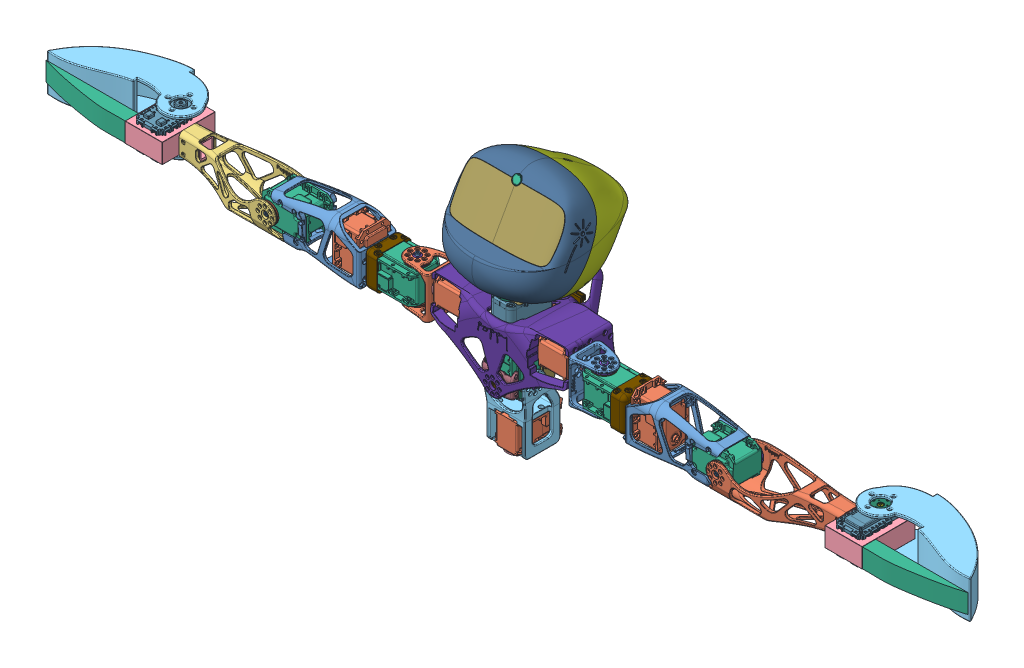
SolidWorks assembly Poppy_Humanoid_Torso_Modify, configuration Default. Lengths in mm.
Overall size (1063.03 305.58 172.17).
144 component instances, 42 part files, 6 mates.
Components (placement in the parent):
- spine-1: spine [Default] at (0 138.4875 17) size (49.29 92.85 54.86)
  - MX-28(T)-2-1: MX-28(T)-2 [Default] x (1 0 0) z (0 -1 0) size (35.6 54.13 45.1)
    - WB_M2.5x8-1: WB_M2.5x8 [Default] at (0 0 25.85) x (0 0 -1) z (-0.991137 0.132843 0) size (10.5 4.5 4.5)
    - dynamixel_x28series(Défaut)-1: dynamixel_x28series(Défaut) [Default] at origin size (35.6 50.71 41.85)
    - trust_washer(Défaut)-1: trust_washer(Défaut) [Default] at (0 0 18.6) x (-0.666375 -0.745617 0) z (0.745617 -0.666375 0) size (22 0.85 22)
    - HN07-N101(Défaut)-1: HN07-N101(Défaut) [Default] at (0 0 18.5) x (1 0 0) z (0 -1 0) size (22 5.85 22)
  - spine-1: spine [Default] at (0 15 0.8) x (-1 0 0) z (0 0 -1) size (49.29 83.95 45.1)
- double_rotation(full_MX28)-1: double_rotation(full_MX28) [Default] at (0 192.4875 19.8) size (48.5 54.13 85.1)
  - MX-28(U)-6-1: MX-28(U)-6 [Default] x (0 0 1) z (1 0 0) size (35.6 54.13 48.5)
    - dynamixel_x28series(U)-1: dynamixel_x28series(U) [Default] at origin size (35.6 50.71 41.85)
    - trust_washer(U)-1: trust_washer(U) [Default] at (0 0 18.6) x (-0.666375 -0.745617 0) z (0.745617 -0.666375 0) size (22 0.85 22)
    - HN07-N101(U)-1: HN07-N101(U) [Default] at (0 0 18.5) x (1 0 0) z (0 -1 0) size (22 5.85 22)
    - WB_M2.5x8-1: WB_M2.5x8 [Default] at (0 0 25.85) x (0 0 -1) z (-0.991137 0.132843 0) size (10.5 4.5 4.5)
    - WB_M2.5x8-2: WB_M2.5x8 [Default] at (0 0 -22.65) x (0 0 1) z (-0.936501 0.350665 0) size (10.5 4.5 4.5)
    - RX28-CAP-1: RX28-CAP [Default] at (0 0 -20.35) x (-0.995735 -0.092256 0) z (0 0 -1) size (7.2 7.2 1.8)
    - MF106ZZ-1: MF106ZZ [Default] at (0 0 -20.35) x (0.888333 -0.4592 0) z (-0.4592 -0.888333 0) size (11.2 3 11.2)
    - HN07-i101-1: HN07-i101 [Default] at (0 0 -20.5) x (1 0 0) z (0 1 0) size (22 3.05 22)
  - MX-28(T)-3-1: MX-28(T)-3 [Default] at (0 0 -37) x (1 0 0) z (0 0 -1) size (35.6 54.13 45.1)
    - WB_M2.5x8-1: WB_M2.5x8 [Default] at (0 0 25.85) x (0 0 -1) z (-0.991137 0.132843 0) size (10.5 4.5 4.5)
    - dynamixel_x28series(Défaut)-1: dynamixel_x28series(Défaut) [Default] at origin size (35.6 50.71 41.85)
    - trust_washer(Défaut)-1: trust_washer(Défaut) [Default] at (0 0 18.6) x (-0.666375 -0.745617 0) z (0.745617 -0.666375 0) size (22 0.85 22)
    - HN07-N101(Défaut)-1: HN07-N101(Défaut) [Default] at (0 0 18.5) x (1 0 0) z (0 -1 0) size (22 5.85 22)
  - i101_Set(FR07)-1: i101_Set(FR07) [Default] at (0 0 21.6) x (-0.798096 0.60253 0) z (0 0 1) size (22 22 3.8)
    - RX28-CAP-1: RX28-CAP [Default] at (0 0 -0.15) size (7.2 7.2 1.8)
    - MF106ZZ-1: MF106ZZ [Default] at (0 0 -0.15) x (-0.837169 0.546944 0) z (-0.546944 -0.837169 0) size (11.2 3 11.2)
    - HN07-i101-1: HN07-i101 [Default] x (1 0 0) z (0 -1 0) size (22 3.05 22)
  - double_rotation_link(double_MX28)-1: double_rotation_link(double_MX28) [Default] at (0 -0.5 0) size (7.4 26.51 14.1)
  - double_rotation_link(double_MX28)-2: double_rotation_link(double_MX28) [Default] at (0 8.5 0) x (-1 0 0) z (0 0 1) size (7.4 26.51 14.1)
  - i101-Set_to_MX_link(MX28_compatible)-1: i101-Set_to_MX_link(MX28_compatible) [Default] x (0 0 -1) z (1 0 0) size (8.29 28.53 35.81)
- chest-1: chest [Default] at (7.2825 216.5654 -159.6611) size (167.7 95.79 102.98)
  - AX-12_18A-1: AX-12_18A [Default] at (-7.2825 38.9221 184.4611) x (-1 0 0) z (0 1 0) size (32 50.04 40.32)
    - dynamixel_AXseries-1: dynamixel_AXseries [Default] at origin size (32 50.04 38.37)
    - AX12_horn-1: AX12_horn [Default] at (0 0 19.1) x (0 1 0) z (0 0 1) size (22 22 6.7)
    - BHS_M2_6X8-1: BHS_M2_6X8 [Default] at (0 0 19.55) x (0.628847 -0.777529 0) z (-0.777529 -0.628847 0) size (5.5 9.6 5.5)
  - MX-28(T)-4-1: MX-28(T)-4 [Default] at (-65.2825 25.9221 183.4611) x (0 -1 0) z (-1 0 0) size (35.6 54.13 45.1)
    - WB_M2.5x8-1: WB_M2.5x8 [Default] at (0 0 25.85) x (0 0 -1) z (-0.991137 0.132843 0) size (10.5 4.5 4.5)
    - dynamixel_x28series(Défaut)-1: dynamixel_x28series(Défaut) [Default] at origin size (35.6 50.71 41.85)
    - trust_washer(Défaut)-1: trust_washer(Défaut) [Default] at (0 0 18.6) x (-0.666375 -0.745617 0) z (0.745617 -0.666375 0) size (22 0.85 22)
    - HN07-N101(Défaut)-1: HN07-N101(Défaut) [Default] at (0 0 18.5) x (1 0 0) z (0 -1 0) size (22 5.85 22)
  - MX-28(T)-5-1: MX-28(T)-5 [Default] at (50.7175 25.9221 183.4611) x (0 1 0) z (1 0 0) size (35.6 54.13 45.1)
    - WB_M2.5x8-1: WB_M2.5x8 [Default] at (0 0 25.85) x (0 0 -1) z (-0.991137 0.132843 0) size (10.5 4.5 4.5)
    - dynamixel_x28series(Défaut)-1: dynamixel_x28series(Défaut) [Default] at origin size (35.6 50.71 41.85)
    - trust_washer(Défaut)-1: trust_washer(Défaut) [Default] at (0 0 18.6) x (-0.666375 -0.745617 0) z (0.745617 -0.666375 0) size (22 0.85 22)
    - HN07-N101(Défaut)-1: HN07-N101(Défaut) [Default] at (0 0 18.5) x (1 0 0) z (0 -1 0) size (22 5.85 22)
  - chest-1: chest [Default] at (-7.2825 -24.0779 121.9611) size (157.02 95.79 102.98)
- shoulder_x-1: shoulder_x [Default] at (119.9166 235.6125 35.5145) x (0 0 -1) z (0 1 0) size (38.6 59.63 48.85)
  - MX-28(U)-7-1: MX-28(U)-7 [Default] at (11.7145 14.4166 -1.625) size (35.6 54.13 48.5)
    - dynamixel_x28series(U)-1: dynamixel_x28series(U) [Default] at origin size (35.6 50.71 41.85)
    - trust_washer(U)-1: trust_washer(U) [Default] at (0 0 18.6) x (-0.666375 -0.745617 0) z (0.745617 -0.666375 0) size (22 0.85 22)
    - HN07-N101(U)-1: HN07-N101(U) [Default] at (0 0 18.5) x (1 0 0) z (0 -1 0) size (22 5.85 22)
    - WB_M2.5x8-1: WB_M2.5x8 [Default] at (0 0 25.85) x (0 0 -1) z (-0.991137 0.132843 0) size (10.5 4.5 4.5)
    - WB_M2.5x8-2: WB_M2.5x8 [Default] at (0 0 -22.65) x (0 0 1) z (-0.936501 0.350665 0) size (10.5 4.5 4.5)
    - RX28-CAP-1: RX28-CAP [Default] at (0 0 -20.35) x (-0.995735 -0.092256 0) z (0 0 -1) size (7.2 7.2 1.8)
    - MF106ZZ-1: MF106ZZ [Default] at (0 0 -20.35) x (0.888333 -0.4592 0) z (-0.4592 -0.888333 0) size (11.2 3 11.2)
    - HN07-i101-1: HN07-i101 [Default] at (0 0 -20.5) x (1 0 0) z (0 1 0) size (22 3.05 22)
  - arm_connector-1: arm_connector [Default] at (11.7145 -28.1834 -11.625) size (38.6 17.77 41.99)
- upper_arm(double_MX-28)-1: upper_arm(double_MX-28) [Default] at (222.8165 235.6388 -24.353) x (0 0 -1) z (0 1 0) size (49.68 127.28 61.97)
  - MX-28(T)-6-1: MX-28(T)-6 [Default] at (-48.153 54.2165 -11.6513) x (1 0 0) z (0 1 0) size (35.6 54.13 45.1)
    - WB_M2.5x8-1: WB_M2.5x8 [Default] at (0 0 25.85) x (0 0 -1) z (-0.991137 0.132843 0) size (10.5 4.5 4.5)
    - dynamixel_x28series(Défaut)-1: dynamixel_x28series(Défaut) [Default] at origin size (35.6 50.71 41.85)
    - trust_washer(Défaut)-1: trust_washer(Défaut) [Default] at (0 0 18.6) x (-0.666375 -0.745617 0) z (0.745617 -0.666375 0) size (22 0.85 22)
    - HN07-N101(Défaut)-1: HN07-N101(Défaut) [Default] at (0 0 18.5) x (1 0 0) z (0 -1 0) size (22 5.85 22)
  - MX-28(U)-8-1: MX-28(U)-8 [Default] at (-48.153 -31.6835 -1.6513) x (0 0 1) z (1 0 0) size (35.6 54.13 48.5)
    - dynamixel_x28series(U)-1: dynamixel_x28series(U) [Default] at origin size (35.6 50.71 41.85)
    - trust_washer(U)-1: trust_washer(U) [Default] at (0 0 18.6) x (-0.666375 -0.745617 0) z (0.745617 -0.666375 0) size (22 0.85 22)
    - HN07-N101(U)-1: HN07-N101(U) [Default] at (0 0 18.5) x (1 0 0) z (0 -1 0) size (22 5.85 22)
    - WB_M2.5x8-1: WB_M2.5x8 [Default] at (0 0 25.85) x (0 0 -1) z (-0.991137 0.132843 0) size (10.5 4.5 4.5)
    - WB_M2.5x8-2: WB_M2.5x8 [Default] at (0 0 -22.65) x (0 0 1) z (-0.936501 0.350665 0) size (10.5 4.5 4.5)
    - RX28-CAP-1: RX28-CAP [Default] at (0 0 -20.35) x (-0.995735 -0.092256 0) z (0 0 -1) size (7.2 7.2 1.8)
    - MF106ZZ-1: MF106ZZ [Default] at (0 0 -20.35) x (0.888333 -0.4592 0) z (-0.4592 -0.888333 0) size (11.2 3 11.2)
    - HN07-i101-1: HN07-i101 [Default] at (0 0 -20.5) x (1 0 0) z (0 1 0) size (22 3.05 22)
  - upper_arm-1: upper_arm [Default] at (-48.153 -31.6835 -1.6513) size (47.66 107.84 61.97)
- forearm(left)-1: forearm(left) [Default] at (312.8543 225.3953 -5.788) x (0 0 -1) z (0 1 0) size (55.2 137.66 53.14)
  - forearm(MX28-left)-1: forearm(MX28-left) [Default] at (-29.588 58.3543 8.5922) size (55.2 137.66 53.14)
- shoulder_x-1-1: shoulder_x-1 [Default] at (-119.9166 235.6125 12.0855) x (0 0 1) z (0 1 0) size (38.6 59.63 48.85)
  - MX-28(U)-9-1: MX-28(U)-9 [Default] at (11.7145 14.4166 -1.625) size (35.6 54.13 48.5)
    - dynamixel_x28series(U)-1: dynamixel_x28series(U) [Default] at origin size (35.6 50.71 41.85)
    - trust_washer(U)-1: trust_washer(U) [Default] at (0 0 18.6) x (-0.666375 -0.745617 0) z (0.745617 -0.666375 0) size (22 0.85 22)
    - HN07-N101(U)-1: HN07-N101(U) [Default] at (0 0 18.5) x (1 0 0) z (0 -1 0) size (22 5.85 22)
    - WB_M2.5x8-1: WB_M2.5x8 [Default] at (0 0 25.85) x (0 0 -1) z (-0.991137 0.132843 0) size (10.5 4.5 4.5)
    - WB_M2.5x8-2: WB_M2.5x8 [Default] at (0 0 -22.65) x (0 0 1) z (-0.936501 0.350665 0) size (10.5 4.5 4.5)
    - RX28-CAP-1: RX28-CAP [Default] at (0 0 -20.35) x (-0.995735 -0.092256 0) z (0 0 -1) size (7.2 7.2 1.8)
    - MF106ZZ-1: MF106ZZ [Default] at (0 0 -20.35) x (0.888333 -0.4592 0) z (-0.4592 -0.888333 0) size (11.2 3 11.2)
    - HN07-i101-1: HN07-i101 [Default] at (0 0 -20.5) x (1 0 0) z (0 1 0) size (22 3.05 22)
  - arm_connector-1: arm_connector [Default] at (11.7145 -28.1834 -11.625) size (38.6 17.77 41.99)
- upper_arm(double-MX-28_Right)-1: upper_arm(double-MX-28_Right) [Default] at (-222.8165 235.6388 71.953) x (0 0 1) z (0 1 0) size (49.68 127.28 61.97)
  - MX-28(T)-7-1: MX-28(T)-7 [Default] at (-48.153 54.2165 -11.6513) x (1 0 0) z (0 1 0) size (35.6 54.13 45.1)
    - WB_M2.5x8-1: WB_M2.5x8 [Default] at (0 0 25.85) x (0 0 -1) z (-0.991137 0.132843 0) size (10.5 4.5 4.5)
    - dynamixel_x28series(Défaut)-1: dynamixel_x28series(Défaut) [Default] at origin size (35.6 50.71 41.85)
    - trust_washer(Défaut)-1: trust_washer(Défaut) [Default] at (0 0 18.6) x (-0.666375 -0.745617 0) z (0.745617 -0.666375 0) size (22 0.85 22)
    - HN07-N101(Défaut)-1: HN07-N101(Défaut) [Default] at (0 0 18.5) x (1 0 0) z (0 -1 0) size (22 5.85 22)
  - MX-28(U)-10-1: MX-28(U)-10 [Default] at (-48.153 -31.6835 -1.6513) x (0 0 -1) z (-1 0 0) size (35.6 54.13 48.5)
    - dynamixel_x28series(U)-1: dynamixel_x28series(U) [Default] at origin size (35.6 50.71 41.85)
    - trust_washer(U)-1: trust_washer(U) [Default] at (0 0 18.6) x (-0.666375 -0.745617 0) z (0.745617 -0.666375 0) size (22 0.85 22)
    - HN07-N101(U)-1: HN07-N101(U) [Default] at (0 0 18.5) x (1 0 0) z (0 -1 0) size (22 5.85 22)
    - WB_M2.5x8-1: WB_M2.5x8 [Default] at (0 0 -22.65) x (0 0 1) z (-0.936501 0.350665 0) size (10.5 4.5 4.5)
    - WB_M2.5x8-2: WB_M2.5x8 [Default] at (0 0 25.85) x (0 0 -1) z (-0.991137 0.132843 0) size (10.5 4.5 4.5)
    - RX28-CAP-1: RX28-CAP [Default] at (0 0 -20.35) x (-0.995735 -0.092256 0) z (0 0 -1) size (7.2 7.2 1.8)
    - MF106ZZ-1: MF106ZZ [Default] at (0 0 -20.35) x (0.888333 -0.4592 0) z (-0.4592 -0.888333 0) size (11.2 3 11.2)
    - HN07-i101-1: HN07-i101 [Default] at (0 0 -20.5) x (1 0 0) z (0 1 0) size (22 3.05 22)
  - upper_arm-1: upper_arm [Default] at (-48.153 -31.6835 -1.6513) size (47.66 107.84 61.97)
- forearm(right)-1: forearm(right) [Default] at (-312.8543 225.3953 53.388) x (0 0 1) z (0 1 0) size (55.2 137.66 53.14)
  - forearm(MX-28-right)-1: forearm(MX-28-right) [Default] at (-29.588 58.3543 8.5922) size (55.2 137.66 53.14)
- head-1: head [Default] at (0 296.4875 24.8) x (1 0 0) z (0 0.34202 0.939693) size (152.35 129.81 135.97)
  - AX-12_18A-1-1: AX-12_18A-1 [Default] x (0 0.939693 0.34202) z (1 0 0) size (32 50.04 40.32)
    - dynamixel_AXseries-1: dynamixel_AXseries [Default] at origin size (32 50.04 38.37)
    - AX12_horn-1: AX12_horn [Default] at (0 0 19.1) x (0 1 0) z (0 0 1) size (22 22 6.7)
    - BHS_M2_6X8-1: BHS_M2_6X8 [Default] at (0 0 19.55) x (0.628847 -0.777529 0) z (-0.777529 -0.628847 0) size (5.5 9.6 5.5)
  - Videw_JDEPC-OV04(170_FOV_lens)-1: Videw_JDEPC-OV04(170_FOV_lens) [Default] at (0 79.5531 9.1743) x (1 0 0) z (0 0.162719 0.986672) size (60.45 10 12.9)
    - Videw_JDEPC-OV04-1: Videw_JDEPC-OV04 [Default] at origin size (60 8 0.6)
    - SM05B-SRSS-TB-1: SM05B-SRSS-TB [Default] at (-23.7 0 0.6) x (0 -1 0) z (-1 0 0) size (7 2.9 4.95)
    - 170_FOV_lens-1: 170_FOV_lens [Default] at (0 0 0.6) size (10 10 12.3)
  - head_back-1: head_back [Default] at origin size (139.97 128.52 115.71)
  - Odroid_U3-1: Odroid_U3 [Default] at (41.5 40.9083 -63.8082) x (1 0 0) z (0 -0.087156 -0.996195) size (83 21.55 48.75)
  - fake_manga_screen-1: fake_manga_screen [Default] at (0 46.1109 21.48) x (1 0 0) z (0 0.162719 0.986672) size (106 70.75 3.7)
  - head_face-1: head_face [Default] at origin size (137.8 118.1 101.78)
  - screen_support-1: screen_support [Default] at origin size (119.01 63.24 19.97)
  - screen-1: screen [Default] at origin size (152.35 100.2 22.24)
  - camera_support-1: camera_support [Default] at (0 0.0163 0.0987) size (81.74 18.94 5.38)
  - VisatonK20.40_speaker-1: VisatonK20.40_speaker [Default] at (-59.643 48.4618 4.5746) x (-0.088219 -0.989732 0.112468) z (-0.984948 0.103522 0.138425) size (40 20 7.34)
  - VisatonK20.40_speaker-2: VisatonK20.40_speaker [Default] at (59.643 48.4618 4.5746) x (0.088219 -0.989732 0.112468) z (0.984948 0.103522 0.138425) size (40 20 7.34)
  - speaker_left-1: speaker_left [Default] at origin size (22.34 61.46 49.54)
  - speaker_right-1: speaker_right [Default] at origin size (22.34 61.46 49.54)
  - 9DOF-Razor-v23-1: 9DOF-Razor-v23 [Default] at (0 23.915 -2) size (41 7.1 28)
- SMPS2Dynamixel-2: SMPS2Dynamixel [Default] at (0 215.4875 -42.45) x (-1 0 0) z (0 0 -1) size (28 54 8.4)
- shoulder(MX-28_Left)-1: shoulder(MX-28_Left) [Default] at (51.5 233.9875 23.8) x (1 0 0) z (0 1 0) size (41.1 39.63 50.34)
- shoulder(MX-28_Right)-1: shoulder(MX-28_Right) [Default] at (-105.5 233.9875 23.8) x (1 0 0) z (0 1 0) size (41.1 39.63 50.34)
- neck-1: neck [Default] at (0 296.4875 24.8) size (48.14 31.5 23.18)
- Gripper_assembled-1: Gripper_assembled [Default] at (372.0424 197.4427 42.2134) x (1 0 0) z (0 1 0) size (177.02 100.6 61.68)
  - AX-12_18A-1-1: AX-12_18A-1 [Default] at (23.4576 40.9134 34.0008) size (32 50.04 40.32)
    - dynamixel_AXseries-1: dynamixel_AXseries [Default] at origin size (32 50.04 38.37)
    - AX12_horn-1: AX12_horn [Default] at (0 0 19.1) x (0 1 0) z (0 0 1) size (22 22 6.7)
    - BHS_M2_6X8-1: BHS_M2_6X8 [Default] at (0 0 19.55) x (0.628847 -0.777529 0) z (-0.777529 -0.628847 0) size (5.5 9.6 5.5)
  - Gripper-1: Gripper [Default] at (-1.4424 28.9134 34.0008) x (1 0 0) z (0 -1 0) size (62 22 60)
  - Gripper Top claw-1: Gripper Top claw [Default] at (23.4576 40.9134 18.0408) x (0 0 1) z (-0.983743 0.179583 0) size (61.68 75.14 148.57)
  - Gripper bottom claw fixed-1: Gripper bottom claw fixed [Default] at (44.4576 14.1634 44.7508) size (104.6 15.83 21.5)
- Gripper_assembled-2: Gripper_assembled [Default] at (-372.0424 265.7379 42.2134) x (-1 0 0) z (0 -1 0) size (177.02 100.6 61.68)
  - AX-12_18A-1-1: AX-12_18A-1 [Default] at (23.4576 40.9134 34.0008) size (32 50.04 40.32)
    - dynamixel_AXseries-1: dynamixel_AXseries [Default] at origin size (32 50.04 38.37)
    - AX12_horn-1: AX12_horn [Default] at (0 0 19.1) x (0 1 0) z (0 0 1) size (22 22 6.7)
    - BHS_M2_6X8-1: BHS_M2_6X8 [Default] at (0 0 19.55) x (0.628847 -0.777529 0) z (-0.777529 -0.628847 0) size (5.5 9.6 5.5)
  - Gripper-1: Gripper [Default] at (-1.4424 28.9134 34.0008) x (1 0 0) z (0 -1 0) size (62 22 60)
  - Gripper Top claw-1: Gripper Top claw [Default] at (23.4576 40.9134 18.0408) x (0 0 1) z (-0.983743 0.179583 0) size (61.68 75.14 148.57)
  - Gripper bottom claw fixed-1: Gripper bottom claw fixed [Default] at (44.4576 14.1634 44.7508) size (104.6 15.83 21.5)
Mates (geometry in assembly coordinates):
- Tangent1: tangent: face of forearm(left)-1/forearm(MX28-left)-1; plane of Gripper_assembled-1/Gripper-1 through (354.5 231.4435 5.3) normal (0 0 -1)
- Tangent2: tangent: face of forearm(left)-1/forearm(MX28-left)-1; plane of Gripper_assembled-1/Gripper-1 through (354.5 231.4435 21.3) normal (0 0 1)
- Coincident1: coincident anti-aligned: plane of forearm(left)-1/forearm(MX28-left)-1 through (374.5 242.9875 -147.401) normal (1 0 0); plane of Gripper_assembled-1/Gripper-1 through (374.5 231.4435 13.3) normal (-1 0 0)
- Coincident2: coincident anti-aligned: plane of forearm(right)-1/forearm(MX-28-right)-1 through (-374.5 242.9875 -147.401) normal (-1 0 0); plane of Gripper_assembled-2/Gripper-1 through (-374.5 231.7371 13.3) normal (1 0 0)
- Tangent3: tangent: face of forearm(right)-1/forearm(MX-28-right)-1; plane of Gripper_assembled-2/Gripper-1 through (-354.5 231.7371 21.3) normal (0 0 1)
- Tangent4: tangent: face of forearm(right)-1/forearm(MX-28-right)-1; plane of Gripper_assembled-2/Gripper-1 through (-354.5 231.7371 5.3) normal (0 0 -1)
